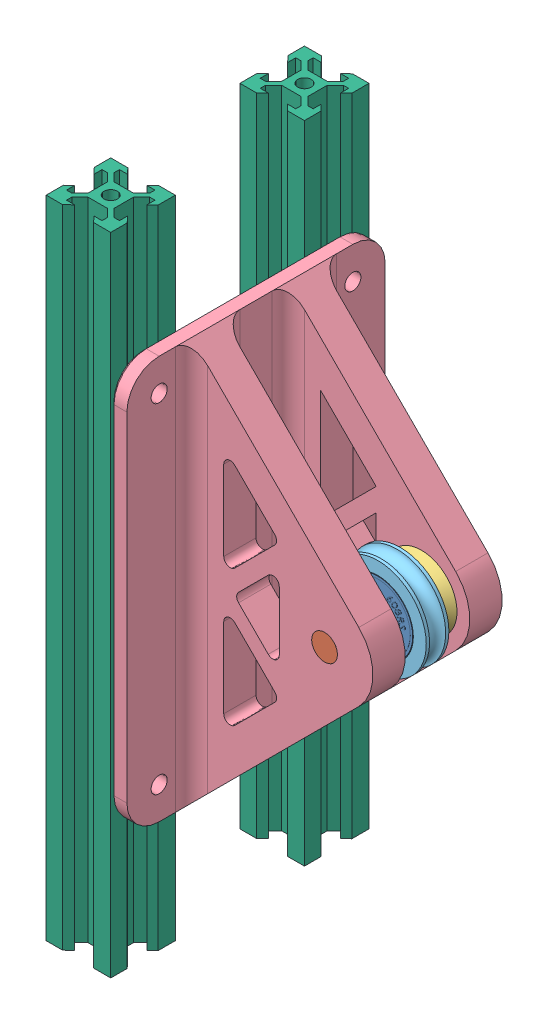
SolidWorks assembly Roldana_de_parede, configuration Valor predeterminado. Lengths in mm.
Overall size (87.44 200 80).
8 component instances, 6 part files, 18 mates.
Components (placement in the parent):
- 608RS-1: 608RS [Default] at (-0.3582 23.9862 26.1008) size (22 22 7)
- Eixo_rolamento-1: Eixo_rolamento [Valor predeterminado] at (-0.3582 23.9862 29.6008) x (0 0 -1) z (-0.777631 -0.628721 0) size (40 8 8)
- Espaçador_rolamento-1: Espaçador_rolamento [Valor predeterminado] at (-0.3582 23.9862 33.1008) size (25.53 26.21 6.5)
- Suporte_de_rolamento-1: Suporte_de_rolamento [Valor predeterminado] at (-41.5913 86.4325 29.6008) x (0 0 1) z (-1 0 0) size (80 124.89 61.23)
- Espaçador_rolamento-2: Espaçador_rolamento [Valor predeterminado] at (-0.3582 23.9862 26.1008) x (-0.923728 -0.383049 0) z (0 0 -1) size (25.53 26.21 6.5)
- Encaixe_corda-1: Encaixe_corda [Valor predeterminado] at (-0.3582 23.9862 33.1008) x (0 0 -1) z (-0.725912 0.687787 0) size (7 30 30)
- Perfil_20x20mm-1: Perfil_20x20mm [200mm] at (-56.5913 -77.8665 -0.3992) size (20 200 20)
- Perfil_20x20mm-2: Perfil_20x20mm [200mm] at (-56.5913 -77.8665 59.6008) size (20 200 20)
Mates (geometry in assembly coordinates):
- Coincidente1: coincident anti-aligned: plane of Suporte_de_rolamento-1 through (-41.5913 86.4325 19.6008) normal (0 0 1); plane of Espaçador_rolamento-2 through (-0.3582 23.9862 19.6008) normal (0 0 -1)
- Coincidente2: coincident anti-aligned: plane of Espaçador_rolamento-1 through (-0.3582 23.9862 39.6008) normal (0 0 1); plane of Suporte_de_rolamento-1 through (-41.5913 86.4325 39.6008) normal (0 0 -1)
- Concêntrico1: concentric anti-aligned: cylinder of Espaçador_rolamento-1 through (-0.3582 23.9862 33.1007) axis (0 0 1) radius 4; cylinder of Suporte_de_rolamento-1 through (-0.3582 23.9862 49.6008) axis (0 0 -1) radius 4
- Concêntrico2: concentric anti-aligned: cylinder of Suporte_de_rolamento-1 through (-0.3582 23.9862 9.6008) axis (0 0 1) radius 4; cylinder of Espaçador_rolamento-2 through (-0.3582 23.9862 26.1009) axis (0 0 -1) radius 4
- Concêntrico3: concentric anti-aligned: cylinder of Eixo_rolamento-1 through (-0.3582 23.9862 9.6008) axis (0 0 1) radius 4; cylinder of Suporte_de_rolamento-1 through (-0.3582 23.9862 49.6008) axis (0 0 -1) radius 4
- Concêntrico4: concentric anti-aligned: cylinder of 608RS-1 through (-0.3582 23.9862 33.1008) axis (0 0 -1) radius 4; cylinder of Eixo_rolamento-1 through (-0.3582 23.9862 9.6008) axis (0 0 1) radius 4
- Coincidente4: coincident anti-aligned: plane of 608RS-1 through (-0.3582 23.9862 33.1008) normal (0 0 1); plane of Espaçador_rolamento-1 through (-0.3582 23.9862 33.1008) normal (0 0 -1)
- Paralelo1: parallel anti-aligned: plane of Suporte_de_rolamento-1 through (-46.5913 86.4325 29.6008) normal (-1 0 0); plane of assembly through (0 0 0) normal (1 0 0)
- Concêntrico5: concentric anti-aligned: cylinder of 608RS-1 through (-0.3582 23.9862 33.1008) axis (0 0 -1) radius 11; cylinder of Encaixe_corda-1 through (-0.3582 23.9862 26.1008) axis (0 0 1) radius 11
- Coincidente6: coincident aligned: plane of 608RS-1 through (-0.3582 23.9862 33.1008) normal (0 0 1); plane of Encaixe_corda-1 through (-0.3582 23.9862 33.1008) normal (0 0 1)
- Coincidente7: coincident aligned: plane of Eixo_rolamento-1 through (-0.3582 23.9862 49.6008) normal (0 0 1); plane of Suporte_de_rolamento-1 through (-41.5913 86.4325 49.6008) normal (0 0 1)
- Coincidente8: coincident anti-aligned: plane of Suporte_de_rolamento-1 through (-46.5913 86.4325 29.6008) normal (-1 0 0); plane of Perfil_20x20mm-1 through (-46.5913 122.1335 -0.3992) normal (1 0 0)
- Coincidente9: coincident anti-aligned: plane of Suporte_de_rolamento-1 through (-46.5913 86.4325 29.6008) normal (-1 0 0); plane of Perfil_20x20mm-2 through (-46.5913 122.1335 59.6008) normal (1 0 0)
- Coincidente10: coincident aligned: plane of Perfil_20x20mm-1 through (-56.5913 122.1335 -0.3992) normal (0 1 0); plane of Perfil_20x20mm-2 through (-56.5913 122.1335 59.6008) normal (0 1 0)
- Coincidente11: coincident aligned: plane of Suporte_de_rolamento-1 through (-46.5913 86.4325 69.6008) normal (0 0 1); plane of Perfil_20x20mm-2 through (-56.5913 122.1335 69.6008) normal (0 0 1)
- Coincidente12: coincident aligned: plane of Suporte_de_rolamento-1 through (-46.5913 86.4325 -10.3992) normal (0 0 -1); plane of Perfil_20x20mm-1 through (-56.5913 122.1335 -10.3992) normal (0 0 -1)
- Coincidente13: coincident: plane of Perfil_20x20mm-2 through (-60.8268 107.5593 49.4037) normal (-1 0 0); plane of ? through (-60.8268 76.7322 59.4037) normal (-1 0 0)
- Coincidente14: coincident anti-aligned: plane of Perfil_20x20mm-2 through (-50.8268 107.5593 59.4037) normal (0 0 1); plane of ? through (-60.8268 76.7322 59.4037) normal (0 0 -1)
